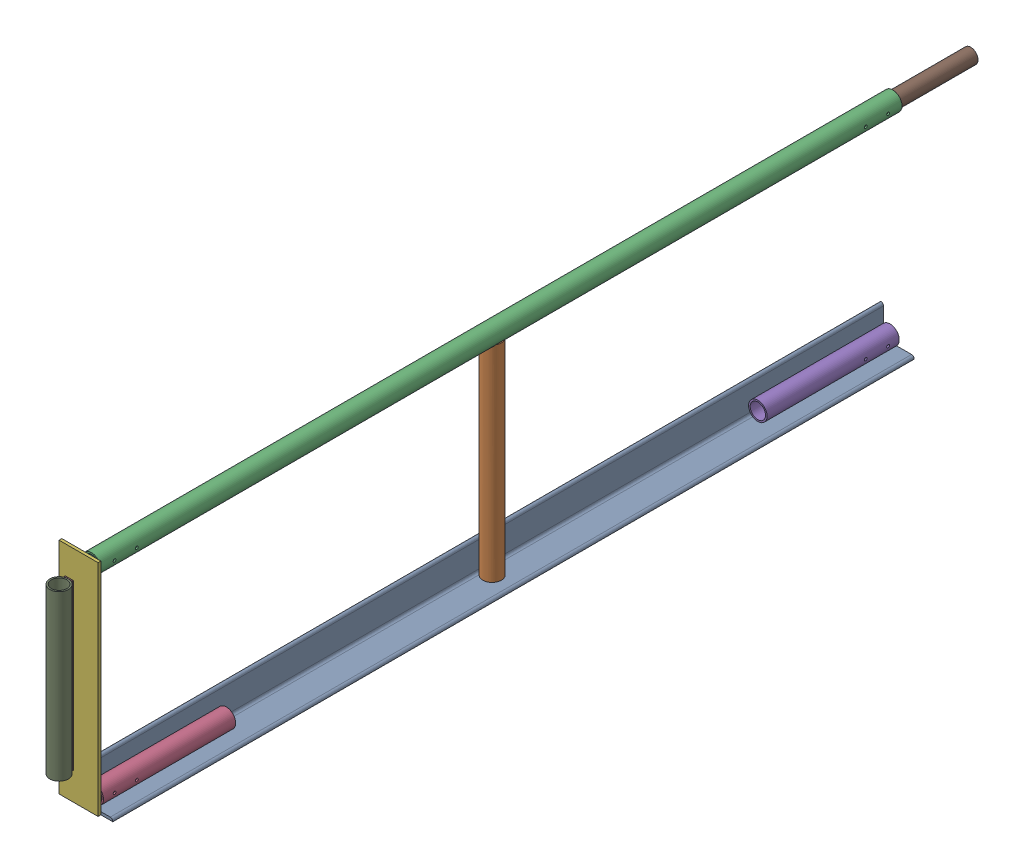
SolidWorks assembly FE-00024_ASM, configuration Default. Lengths in mm.
Overall size (109.89 508 2063.85).
13 component instances, 9 part files, 0 mates.
Components (placement in the parent):
- FE-00005_ASM-1: FE-00005_ASM [Default] at origin size (76.2 507.65 1828.8)
  - FE-00005-01-1: FE-00005-01 [Default] at origin size (76.2 76.2 1828.8)
  - FE-00005-03-1: FE-00005-03 [Default] at (27.432 6.35 914.4) size (42.16 471.23 42.16)
  - FE-00005-04-1: FE-00005-04 [Default] at (27.432 486.5688 0) size (42.16 42.16 1828.8)
  - FE-00005-02-1: FE-00005-02 [Default] at (27.432 27.432 1520.825) size (42.16 42.16 301.62)
  - FE-00005-02-2: FE-00005-02 [Default] at (27.432 27.432 307.975) x (1 0 0) z (0 0 -1) size (42.16 42.16 301.62)
- FE-00018_ASM-1: FE-00018_ASM [Default] at (-33.6868 6.35 1835.15) size (88.9 501.65 152.5)
  - FE-00018-03-1: FE-00018-03 [Default] at origin size (88.9 501.65 6.35)
  - FE-00018-02-1: FE-00018-02 [Default] at (61.1187 480.2188 -101.6) size (33.4 33.4 101.6)
  - FE-00018-02-2: FE-00018-02 [Default] at (61.1124 21.4312 -101.6) size (33.4 33.4 101.6)
  - FE-00018-01-1: FE-00018-01 [Default] at (23.368 63.5 29.8196) x (1 0 0) z (0 1 0) size (42.16 42.16 374.65)
  - FE-00018-04-1: FE-00018-04 [Default] at (23.368 250.825 6.35) size (19.05 374.65 2.38)
- FE-00026-1: FE-00026 [Default] at (27.432 486.5688 177.8) x (-1 0 0) z (0 0 -1) size (33.4 33.4 355.6)
